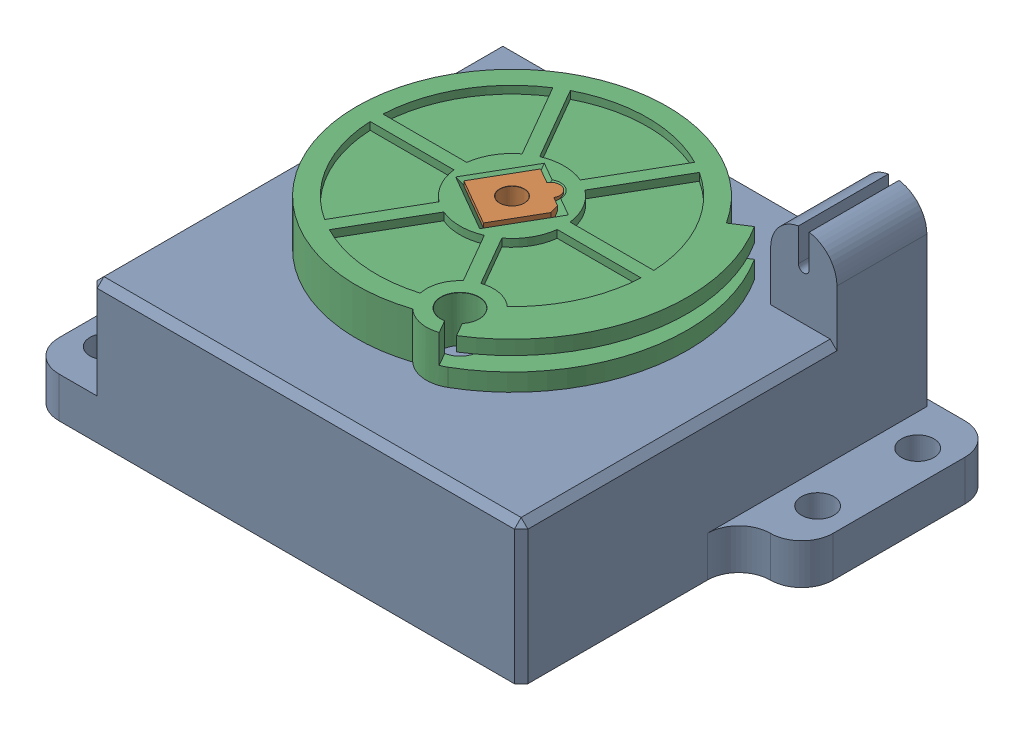
SolidWorks assembly Montagem Acelerador, configuration Valor predeterminado. Lengths in mm.
Overall size (82.3 32.93 64.29).
3 component instances, 3 part files, 6 mates.
Components (placement in the parent):
- Base-1: Base [Valor predeterminado] at (-11.0663 -18.0845 30.5) size (82.3 32.93 61)
- Eixo-1: Eixo [Valor predeterminado] at (-11.0663 -11.8845 30.5) x (0.866025 0 0.5) z (-0.5 0 0.866025) size (12.4 27.6 12.4)
- Acoplamento cabo-1: Acoplamento cabo [Valor predeterminado] at (-11.0663 10.3155 30.5) x (0.866025 0 0.5) z (-0.5 0 0.866025) size (48.9 6.8 46)
Mates (geometry in assembly coordinates):
- Concêntrico1: concentric anti-aligned: cylinder of Base-1 through (-11.0663 -14.0845 30.5) axis (0 1 0) radius 6.25; cylinder of Eixo-1 through (-11.0663 6.2155 30.5) axis (0 -1 0) radius 6.2
- ÂnguloLimite1: limit planar angle = 1.047198 rad anti-aligned: plane of Base-1 through (-14.0776 -11.8845 34.8005) normal (0.819152 0 0.573576); plane of Eixo-1 through (-8.8687 -13.8845 35.2128) normal (-0.906308 0 0.422618)
- Coincidente1: coincident aligned: plane of Base-1 through (-11.0663 6.2155 30.5) normal (0 1 0); plane of Eixo-1 through (-11.0663 6.2155 30.5) normal (0 1 0)
- Concêntrico2: concentric anti-aligned: cylinder of Eixo-1 through (-11.0663 13.7155 30.5) axis (0 1 0) radius 1.8; cylinder of Acoplamento cabo-1 through (-11.0663 13.7155 30.5) axis (0 -1 0) radius 22.95
- Paralelo1: parallel anti-aligned: plane of Eixo-1 through (-12.4121 13.7155 24.931) normal (-0.866025 0 -0.5); plane of Acoplamento cabo-1 through (-12.5005 6.9155 25.2841) normal (0.866025 0 0.5)
- Coincidente3: coincident aligned: plane of Eixo-1 through (-8.9913 13.7155 26.906) normal (0 1 0); plane of Acoplamento cabo-1 through (-11.0663 13.7155 30.5) normal (0 1 0)
